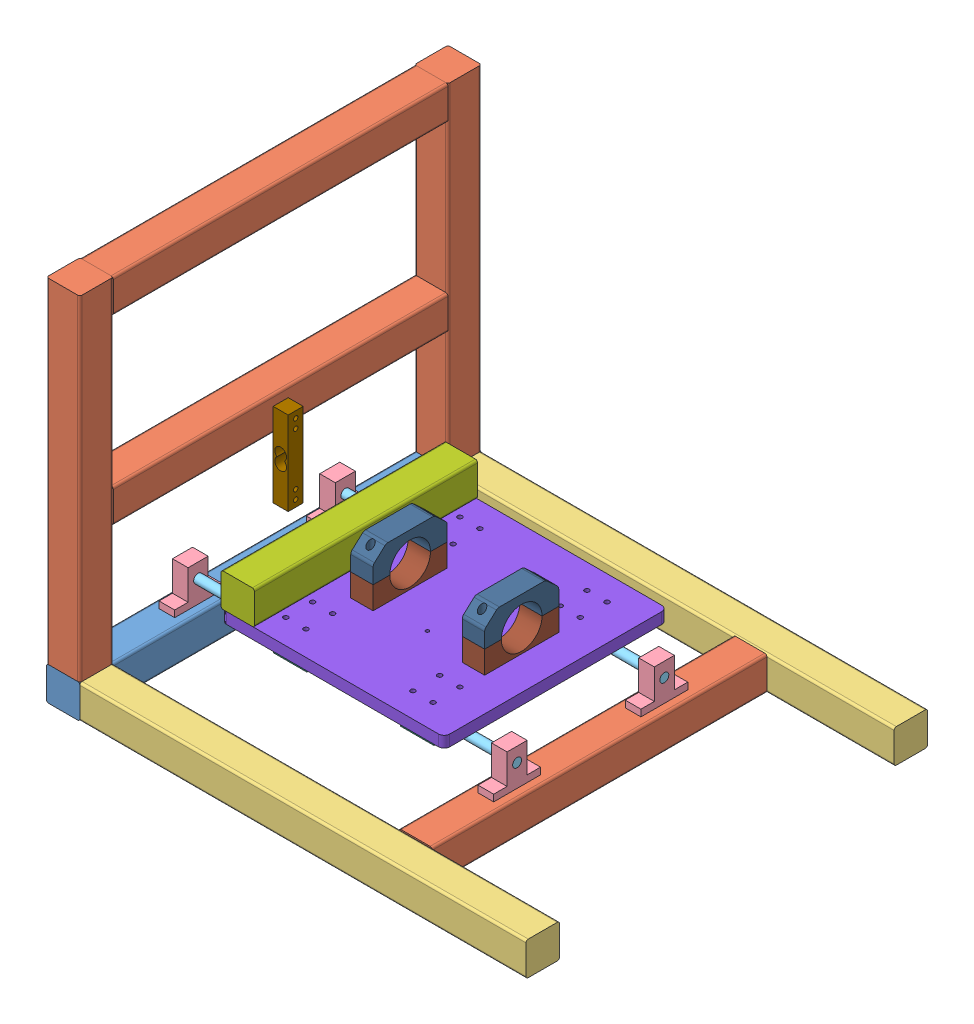
SolidWorks assembly platform, configuration Default. Lengths in mm.
Overall size (430 330 360).
25 component instances, 11 part files, 68 mates.
Components (placement in the parent):
- 3030M-2-360-1: 3030M-2-360 [Default] at (98.2892 189.1661 96.3863) size (30 30 360)
- 3030M-2-300-1: 3030M-2-300 [Default] at (98.2892 219.1661 456.3863) x (1 0 0) z (0 1 0) size (30 30 300)
- 3030M-2-300-2: 3030M-2-300 [Default] at (98.2892 219.1661 126.3863) x (1 0 0) z (0 1 0) size (30 30 300)
- 3030M-2-300-3: 3030M-2-300 [Default] at (98.2892 489.1661 126.3863) size (30 30 300)
- 3030M-2-400-1: 3030M-2-400 [Default] at (128.2892 189.1661 456.3863) x (0 0 -1) z (1 0 0) size (30 30 400)
- 3030M-2-400-2: 3030M-2-400 [Default] at (128.2892 189.1661 126.3863) x (0 0 -1) z (1 0 0) size (30 30 400)
- 3030M-2-300-4: 3030M-2-300 [Default] at (384.2892 189.1661 126.3863) size (30 30 300)
- 3030M-2-300-5: 3030M-2-300 [Default] at (98.2892 326.1661 126.3863) size (30 30 300)
- foot-8-1: foot-8 [Default] at (406.2892 219.1661 321.3863) x (0 0 1) z (-1 0 0) size (42 32.8 14)
- foot-8-2: foot-8 [Default] at (406.2892 219.1661 189.3863) x (0 0 1) z (-1 0 0) size (42 32.8 14)
- stick-8-400-1: stick-8-400 [Default] at (106.2892 239.1661 342.3863) x (0 0.485348 -0.874321) z (1 0 0) size (16 16 300)
- slider-1: slider [Default] at (234.8807 250.1661 325.3863) x (0 0 1) z (-1 0 0) size (34 22 30)
- slider-2: slider [Default] at (348.8807 250.1661 325.3863) x (0 0 1) z (-1 0 0) size (34 22 30)
- foot-8-3: foot-8 [Default] at (106.2892 219.1661 363.3863) x (0 0 -1) z (1 0 0) size (42 32.8 14)
- slider-5: slider [Default] at (348.8807 250.1661 193.3863) x (0 0 1) z (-1 0 0) size (34 22 30)
- slider-6: slider [Default] at (234.8807 250.1661 193.3863) x (0 0 1) z (-1 0 0) size (34 22 30)
- stick-8-400-4: stick-8-400 [Default] at (106.2892 239.1661 210.3863) x (0 0.159355 -0.987221) z (1 0 0) size (16 16 300)
- foot-8-5: foot-8 [Default] at (106.2892 219.1661 231.3863) x (0 0 -1) z (1 0 0) size (42 32.8 14)
- 3030M-2-200-1: 3030M-2-200 [Default] at (174.8807 260.1661 176.3863) size (30 30 200)
- plate-new-1: plate-new [Default] at (190.8807 260.1661 176.3863) x (1 0 0) z (0 -1 0) size (200 200 10)
- sensor-1: sensor [Default] at (141.7892 347.1661 269.6363) x (0 -1 0) z (-1 0 0) size (75 13.5 13.5)
- fixture-upper-1: fixture-upper [Default] at (244.8807 280.4161 276.8863) x (0 0 1) z (-1 0 0) size (66.5 26.09 20)
- fixture-lower-1: fixture-lower [Default] at (244.8807 280.4161 276.8863) x (0 0 -1) z (-1 0 0) size (66.5 20.25 20)
- fixture-lower-2: fixture-lower [Default] at (344.8807 280.4161 276.8863) x (0 0 -1) z (-1 0 0) size (66.5 20.25 20)
- fixture-upper-2: fixture-upper [Default] at (324.8807 280.4161 276.8863) x (0 0 -1) z (1 0 0) size (66.5 26.09 20)
Mates (geometry in assembly coordinates):
- Coincident1: coincident anti-aligned: plane of 3030M-2-360-1 through (126.2892 219.1661 456.3863) normal (0 1 0); plane of 3030M-2-300-1 through (100.2892 219.1661 454.3863) normal (0 -1 0)
- Coincident2: coincident anti-aligned: line of 3030M-2-360-1 through (126.2892 219.1661 456.3863) axis (-1 0 0); line of 3030M-2-300-1 through (100.2892 219.1661 456.3863) axis (1 0 0)
- Coincident3: coincident aligned: plane of 3030M-2-360-1 through (128.2892 191.1661 456.3863) normal (1 0 0); plane of 3030M-2-300-1 through (128.2892 519.1661 454.3863) normal (1 0 0)
- Coincident4: coincident anti-aligned: plane of 3030M-2-360-1 through (126.2892 219.1661 456.3863) normal (0 1 0); plane of 3030M-2-300-2 through (100.2892 219.1661 124.3863) normal (0 -1 0)
- Coincident5: coincident aligned: plane of 3030M-2-360-1 through (100.2892 191.1661 96.3863) normal (0 0 -1); plane of 3030M-2-300-2 through (126.2892 519.1661 96.3863) normal (0 0 -1)
- Coincident6: coincident aligned: plane of 3030M-2-360-1 through (128.2892 191.1661 456.3863) normal (1 0 0); plane of 3030M-2-300-2 through (128.2892 519.1661 124.3863) normal (1 0 0)
- Coincident7: coincident aligned: plane of 3030M-2-300-1 through (128.2892 519.1661 454.3863) normal (1 0 0); plane of 3030M-2-300-3 through (128.2892 491.1661 426.3863) normal (1 0 0)
- Coincident8: coincident anti-aligned: plane of 3030M-2-300-2 through (100.2892 519.1661 126.3863) normal (0 0 1); plane of 3030M-2-300-3 through (100.2892 491.1661 126.3863) normal (0 0 -1)
- Coincident9: coincident aligned: plane of 3030M-2-300-2 through (100.2892 519.1661 124.3863) normal (0 1 0); plane of 3030M-2-300-3 through (126.2892 519.1661 426.3863) normal (0 1 0)
- Coincident10: coincident anti-aligned: plane of 3030M-2-360-1 through (128.2892 191.1661 456.3863) normal (1 0 0); plane of 3030M-2-400-1 through (128.2892 191.1661 454.3863) normal (-1 0 0)
- Coincident11: coincident aligned: plane of 3030M-2-360-1 through (126.2892 219.1661 456.3863) normal (0 1 0); plane of 3030M-2-400-1 through (528.2892 219.1661 428.3863) normal (0 1 0)
- Coincident12: coincident aligned: plane of 3030M-2-360-1 through (100.2892 191.1661 456.3863) normal (0 0 1); plane of 3030M-2-400-1 through (528.2892 217.1661 456.3863) normal (0 0 1)
- Coincident13: coincident anti-aligned: plane of 3030M-2-360-1 through (128.2892 191.1661 456.3863) normal (1 0 0); plane of 3030M-2-400-2 through (128.2892 191.1661 124.3863) normal (-1 0 0)
- Coincident14: coincident aligned: plane of 3030M-2-360-1 through (100.2892 191.1661 96.3863) normal (0 0 -1); plane of 3030M-2-400-2 through (528.2892 191.1661 96.3863) normal (0 0 -1)
- Coincident15: coincident aligned: plane of 3030M-2-360-1 through (126.2892 219.1661 456.3863) normal (0 1 0); plane of 3030M-2-400-2 through (528.2892 219.1661 98.3863) normal (0 1 0)
- Coincident16: coincident anti-aligned: plane of 3030M-2-400-1 through (528.2892 191.1661 426.3863) normal (0 0 -1); plane of 3030M-2-300-4 through (386.2892 191.1661 426.3863) normal (0 0 1)
- Coincident17: coincident aligned: plane of 3030M-2-400-1 through (528.2892 219.1661 428.3863) normal (0 1 0); plane of 3030M-2-300-4 through (412.2892 219.1661 426.3863) normal (0 1 0)
- Coincident18: coincident aligned: plane of 3030M-2-360-1 through (128.2892 191.1661 456.3863) normal (1 0 0); plane of 3030M-2-300-5 through (128.2892 328.1661 426.3863) normal (1 0 0)
- Coincident19: coincident anti-aligned: plane of 3030M-2-300-1 through (126.2892 519.1661 426.3863) normal (0 0 -1); plane of 3030M-2-300-5 through (100.2892 328.1661 426.3863) normal (0 0 1)
- Coincident20: coincident anti-aligned: plane of 3030M-2-300-4 through (412.2892 219.1661 426.3863) normal (0 1 0); plane of foot-8-1 through (392.2892 219.1661 321.3863) normal (0 -1 0)
- Distance1: distance = 8 mm aligned: plane of foot-8-1 through (406.2892 219.1661 321.3863) normal (1 0 0); plane of 3030M-2-300-4 through (414.2892 191.1661 426.3863) normal (1 0 0)
- Coincident23: coincident aligned: plane of foot-8-1 through (406.2892 219.1661 321.3863) normal (1 0 0); plane of foot-8-2 through (406.2892 219.1661 189.3863) normal (1 0 0)
- Coincident24: coincident anti-aligned: plane of 3030M-2-300-4 through (412.2892 219.1661 426.3863) normal (0 1 0); plane of foot-8-2 through (392.2892 219.1661 189.3863) normal (0 -1 0)
- Concentric1: concentric anti-aligned: cylinder of foot-8-1 through (392.2892 239.1661 342.3863) axis (1 0 0) radius 4; cylinder of stick-8-400-1 through (406.2892 239.1661 342.3863) axis (-1 0 0) radius 4
- Concentric2: concentric anti-aligned: cylinder of stick-8-400-1 through (406.2892 239.1661 342.3863) axis (-1 0 0) radius 4; cylinder of slider-1 through (204.8807 239.1661 342.3863) axis (1 0 0) radius 4
- Parallel1: parallel aligned: plane of 3030M-2-400-1 through (528.2892 219.1661 428.3863) normal (0 1 0); plane of slider-1 through (204.8807 250.1661 325.3863) normal (0 1 0)
- Concentric11: concentric anti-aligned: cylinder of stick-8-400-1 through (406.2892 239.1661 342.3863) axis (-1 0 0) radius 4; cylinder of slider-2 through (318.8807 239.1661 342.3863) axis (1 0 0) radius 4
- Parallel2: parallel aligned: plane of 3030M-2-400-1 through (528.2892 219.1661 428.3863) normal (0 1 0); plane of slider-2 through (318.8807 250.1661 325.3863) normal (0 1 0)
- Coincident36: coincident aligned: plane of foot-8-1 through (406.2892 219.1661 321.3863) normal (1 0 0); plane of stick-8-400-1 through (406.2892 239.1661 342.3863) normal (1 0 0)
- Coincident37: coincident anti-aligned: plane of 3030M-2-360-1 through (126.2892 219.1661 456.3863) normal (0 1 0); plane of foot-8-3 through (120.2892 219.1661 363.3863) normal (0 -1 0)
- Distance4: distance = 8 mm aligned: plane of foot-8-3 through (120.2892 219.1661 363.3863) normal (1 0 0); plane of 3030M-2-360-1 through (128.2892 191.1661 456.3863) normal (1 0 0)
- Coincident40: coincident aligned: plane of stick-8-400-1 through (106.2892 239.1661 342.3863) normal (-1 0 0); plane of foot-8-3 through (106.2892 219.1661 363.3863) normal (-1 0 0)
- Concentric32: concentric anti-aligned: cylinder of foot-8-2 through (392.2892 239.1661 210.3863) axis (1 0 0) radius 4; cylinder of stick-8-400-4 through (406.2892 239.1661 210.3863) axis (-1 0 0) radius 4
- Coincident58: coincident aligned: plane of foot-8-2 through (406.2892 219.1661 189.3863) normal (1 0 0); plane of stick-8-400-4 through (406.2892 239.1661 210.3863) normal (1 0 0)
- Concentric33: concentric anti-aligned: cylinder of slider-6 through (204.8807 239.1661 210.3863) axis (1 0 0) radius 4; cylinder of stick-8-400-4 through (406.2892 239.1661 210.3863) axis (-1 0 0) radius 4
- Concentric34: concentric anti-aligned: cylinder of slider-5 through (318.8807 239.1661 210.3863) axis (1 0 0) radius 4; cylinder of stick-8-400-4 through (406.2892 239.1661 210.3863) axis (-1 0 0) radius 4
- Parallel4: parallel aligned: plane of 3030M-2-400-2 through (528.2892 219.1661 98.3863) normal (0 1 0); plane of slider-6 through (204.8807 250.1661 193.3863) normal (0 1 0)
- Parallel5: parallel aligned: plane of 3030M-2-400-2 through (528.2892 219.1661 98.3863) normal (0 1 0); plane of slider-5 through (318.8807 250.1661 193.3863) normal (0 1 0)
- Coincident61: coincident aligned: plane of foot-8-3 through (106.2892 219.1661 363.3863) normal (-1 0 0); plane of foot-8-5 through (106.2892 219.1661 231.3863) normal (-1 0 0)
- Coincident62: coincident anti-aligned: plane of 3030M-2-360-1 through (126.2892 219.1661 456.3863) normal (0 1 0); plane of foot-8-5 through (120.2892 219.1661 231.3863) normal (0 -1 0)
- Coincident64: coincident aligned: plane of foot-8-2 through (392.2892 251.9661 201.3863) normal (0 0 -1); plane of foot-8-5 through (120.2892 225.1661 201.3863) normal (0 0 -1)
- Coincident65: coincident aligned: plane of foot-8-1 through (392.2892 225.1661 351.3863) normal (0 0 1); plane of foot-8-3 through (120.2892 251.9661 351.3863) normal (0 0 1)
- Coincident68: coincident aligned: plane of slider-1 through (204.8807 250.1661 325.3863) normal (-1 0 0); plane of slider-6 through (204.8807 250.1661 193.3863) normal (-1 0 0)
- Coincident69: coincident aligned: plane of slider-2 through (348.8807 250.1661 325.3863) normal (1 0 0); plane of slider-5 through (348.8807 250.1661 193.3863) normal (1 0 0)
- Coincident70: coincident anti-aligned: plane of slider-6 through (204.8807 250.1661 193.3863) normal (0 1 0); plane of plate-new-1 through (369.8807 250.1661 371.3863) normal (0 -1 0)
- Concentric35: concentric anti-aligned: cylinder of slider-6 through (210.8807 250.1661 198.3863) axis (0 -1 0) radius 2; cylinder of plate-new-1 through (210.8807 250.1661 198.3863) axis (0 1 0) radius 2.1
- Concentric36: concentric anti-aligned: cylinder of slider-5 through (324.8807 250.1661 198.3863) axis (0 -1 0) radius 2; cylinder of plate-new-1 through (324.8807 250.1661 198.3863) axis (0 1 0) radius 2.1
- Concentric38: concentric anti-aligned: cylinder of slider-2 through (324.8807 250.1661 354.3863) axis (0 -1 0) radius 2; cylinder of plate-new-1 through (324.8807 250.1661 354.3863) axis (0 1 0) radius 2.1
- Coincident71: coincident anti-aligned: plane of 3030M-2-200-1 through (176.8807 260.1661 376.3863) normal (0 -1 0); plane of plate-new-1 through (369.8807 260.1661 371.3863) normal (0 1 0)
- Coincident72: coincident aligned: plane of 3030M-2-200-1 through (174.8807 288.1661 376.3863) normal (-1 0 0); plane of plate-new-1 through (174.8807 250.1661 371.3863) normal (-1 0 0)
- Coincident73: coincident aligned: plane of 3030M-2-200-1 through (176.8807 262.1661 376.3863) normal (0 0 1); plane of plate-new-1 through (369.8807 250.1661 376.3863) normal (0 0 1)
- Distance6: distance = 105 mm aligned: plane of foot-8-5 through (120.2892 225.1661 201.3863) normal (0 0 -1); plane of 3030M-2-300-2 through (126.2892 519.1661 96.3863) normal (0 0 -1)
- Coincident74: coincident anti-aligned: plane of 3030M-2-300-5 through (128.2892 328.1661 426.3863) normal (1 0 0); plane of sensor-1 through (128.2892 347.1661 269.6363) normal (-1 0 0)
- Distance7: distance = 15 mm aligned: plane of sensor-1 through (141.7892 341.1661 269.6363) normal (0 1 0); plane of 3030M-2-300-5 through (126.2892 356.1661 426.3863) normal (0 1 0)
- Distance8: distance = 150 mm anti-aligned: plane of sensor-1 through (141.7892 347.1661 276.3863) normal (0 0 -1); plane of 3030M-2-300-2 through (100.2892 519.1661 126.3863) normal (0 0 1)
- Distance9: distance = 18 mm anti-aligned: plane of sensor-1 through (128.2892 272.1661 269.6363) normal (0 -1 0); plane of 3030M-2-200-1 through (202.8807 290.1661 376.3863) normal (0 1 0)
- Coincident75: coincident anti-aligned: plane of plate-new-1 through (369.8807 260.1661 371.3863) normal (0 1 0); plane of fixture-lower-1 through (224.8807 260.1661 310.1363) normal (0 -1 0)
- Concentric39: concentric anti-aligned: cylinder of plate-new-1 through (234.8807 250.1661 251.3863) axis (0 1 0) radius 1.5; cylinder of fixture-lower-1 through (234.8807 280.4161 251.3863) axis (0 -1 0) radius 3
- Parallel7: parallel anti-aligned: plane of 3030M-2-200-1 through (204.8807 262.1661 376.3863) normal (1 0 0); plane of fixture-lower-1 through (224.8807 280.4161 276.8863) normal (-1 0 0)
- Coincident77: coincident anti-aligned: plane of fixture-upper-1 through (224.8807 280.4161 243.6363) normal (0 -1 0); plane of fixture-lower-1 through (224.8807 280.4161 258.6363) normal (0 1 0)
- Concentric42: concentric anti-aligned: cylinder of fixture-upper-1 through (234.8807 286.5045 251.3863) axis (0 1 0) radius 3; cylinder of fixture-lower-1 through (234.8807 280.4161 251.3863) axis (0 -1 0) radius 3
- Coincident78: coincident aligned: plane of fixture-upper-1 through (224.8807 293.9436 247.6363) normal (-1 0 0); plane of fixture-lower-1 through (224.8807 280.4161 276.8863) normal (-1 0 0)
- Coincident79: coincident anti-aligned: plane of plate-new-1 through (369.8807 260.1661 371.3863) normal (0 1 0); plane of fixture-lower-2 through (324.8807 260.1661 310.1363) normal (0 -1 0)
- Concentric43: concentric anti-aligned: cylinder of plate-new-1 through (334.8807 250.1661 251.3863) axis (0 1 0) radius 1.5; cylinder of fixture-lower-2 through (334.8807 280.4161 251.3863) axis (0 -1 0) radius 3
- Parallel8: parallel anti-aligned: plane of 3030M-2-200-1 through (204.8807 262.1661 376.3863) normal (1 0 0); plane of fixture-lower-2 through (324.8807 280.4161 276.8863) normal (-1 0 0)
- Coincident81: coincident anti-aligned: plane of fixture-lower-2 through (324.8807 280.4161 258.6363) normal (0 1 0); plane of fixture-upper-2 through (344.8807 280.4161 258.6363) normal (0 -1 0)
- Concentric44: concentric anti-aligned: cylinder of fixture-lower-2 through (334.8807 280.4161 251.3863) axis (0 -1 0) radius 3; cylinder of fixture-upper-2 through (334.8807 286.5045 251.3863) axis (0 1 0) radius 3
- Coincident82: coincident aligned: plane of fixture-lower-2 through (324.8807 280.4161 276.8863) normal (-1 0 0); plane of fixture-upper-2 through (324.8807 293.9436 306.1363) normal (-1 0 0)
